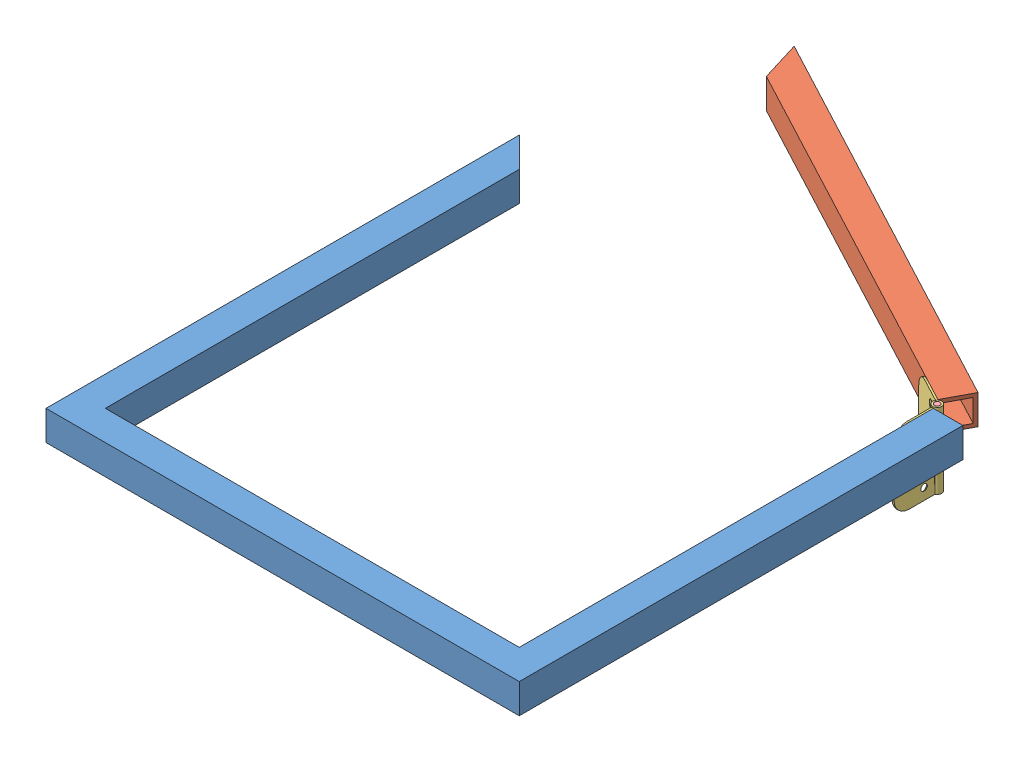
SolidWorks assembly frame, configuration Default. Lengths in mm.
Overall size (399 63.5 579.78).
6 component instances, 4 part files, 6 mates.
Components (placement in the parent):
- u-part1-1: u-part1 [Default] at (122.8343 162.7552 342.436) size (399 25 399)
- u-part2-1: u-part2 [Default] at (58.8326 162.7552 228.4274) x (0.88327 0 0.468865) z (-0.468865 0 0.88327) size (374 25 25)
- Hinge_01-2: Hinge_01 [Default] at (295.8103 124.2552 201.0221) x (0 0 1) z (0 -1 0) size (59.41 40.75 63.5)
  - Hinge_01-1: Hinge_01 [Default] at origin size (42 7.8 63.5)
  - Hinge_01-2: Hinge_01 [Default] at (-56.0759 33.72 -63.5) x (-0.468865 0.88327 0) z (0 0 -1) size (42 7.8 63.5)
  - Hinge_01_Pin-1: Hinge_01_Pin [Default] at (-56.0759 33.72 -63.5) x (-0.468865 0.88327 0) z (0 0 -1) size (4.75 4.75 63.5)
Mates (geometry in assembly coordinates):
- Coincident3: coincident aligned: plane of u-part1-1 through (122.8343 187.7552 342.436) normal (0 1 0); plane of Hinge_01-2/Hinge_01-1 through (439.9755 187.7552 166.9097) normal (0 1 0)
- Coincident4: coincident anti-aligned: plane of u-part1-1 through (297.3343 187.7552 342.436) normal (-1 0 0); plane of Hinge_01-2/Hinge_01-1 through (297.3343 187.7552 166.9097) normal (1 0 0)
- Lock1: lock: unknown of u-part1-1; unknown of Hinge_01-2/Hinge_01-1
- Coincident6: coincident aligned: plane of u-part2-1 through (58.8326 187.7552 228.4274) normal (0 1 0); plane of ? through (359.8147 187.7552 33.6034) normal (0 1 0)
- Coincident7: coincident anti-aligned: plane of u-part2-1 through (-15.3279 187.7552 -4.0409) normal (-0.468865 0 0.88327); plane of ? through (292.9352 124.2552 159.5941) normal (0.468865 0 -0.88327)
- Lock3: lock: unknown of u-part2-1; unknown of ?
